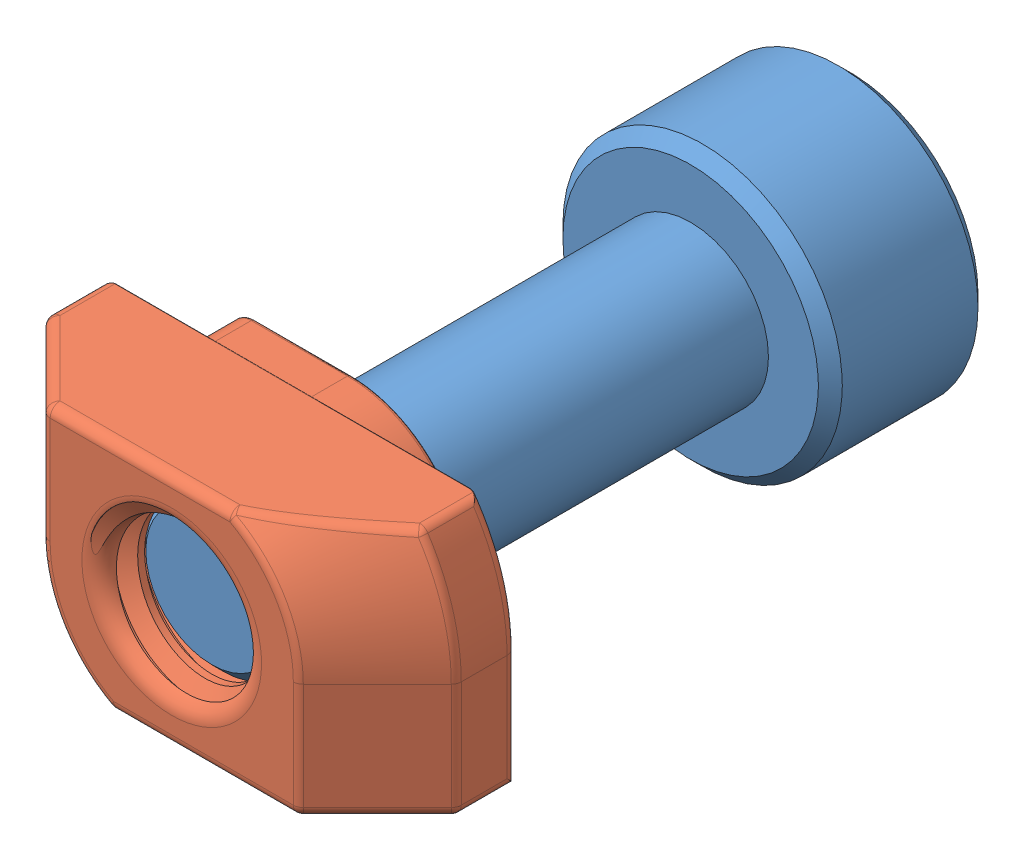
SolidWorks assembly M4x12+TNut, configuration Default. Lengths in mm.
Overall size (10.3 7 17.23).
2 component instances, 2 part files, 2 mates.
Components (placement in the parent):
- M4x12-1: M4x12 [Default] at (-33.9966 -12.6512 18.5345) size (7 7 16)
- T-Nut M4 20 Series-1: T-Nut M4 20 Series [Default] at (-33.9966 -12.6512 35.5345) x (1 0 0) z (0 1 0) size (10.3 4.96 5.96)
Mates (geometry in assembly coordinates):
- Konzentrisch1: concentric anti-aligned: cylinder of M3x12-1 through (-33.9966 -12.6512 34.5345) axis (0 0 -1) radius 1.95; circle of T-Nut M4 20 Series-1
- Abstand1: distance = 1 mm aligned: plane of M4x12-1 through (-33.9966 -12.6512 34.5345) normal (0 0 1); plane of T-Nut M4 20 Series-1 through (-33.9966 -12.6512 35.5345) normal (0 0 1)
